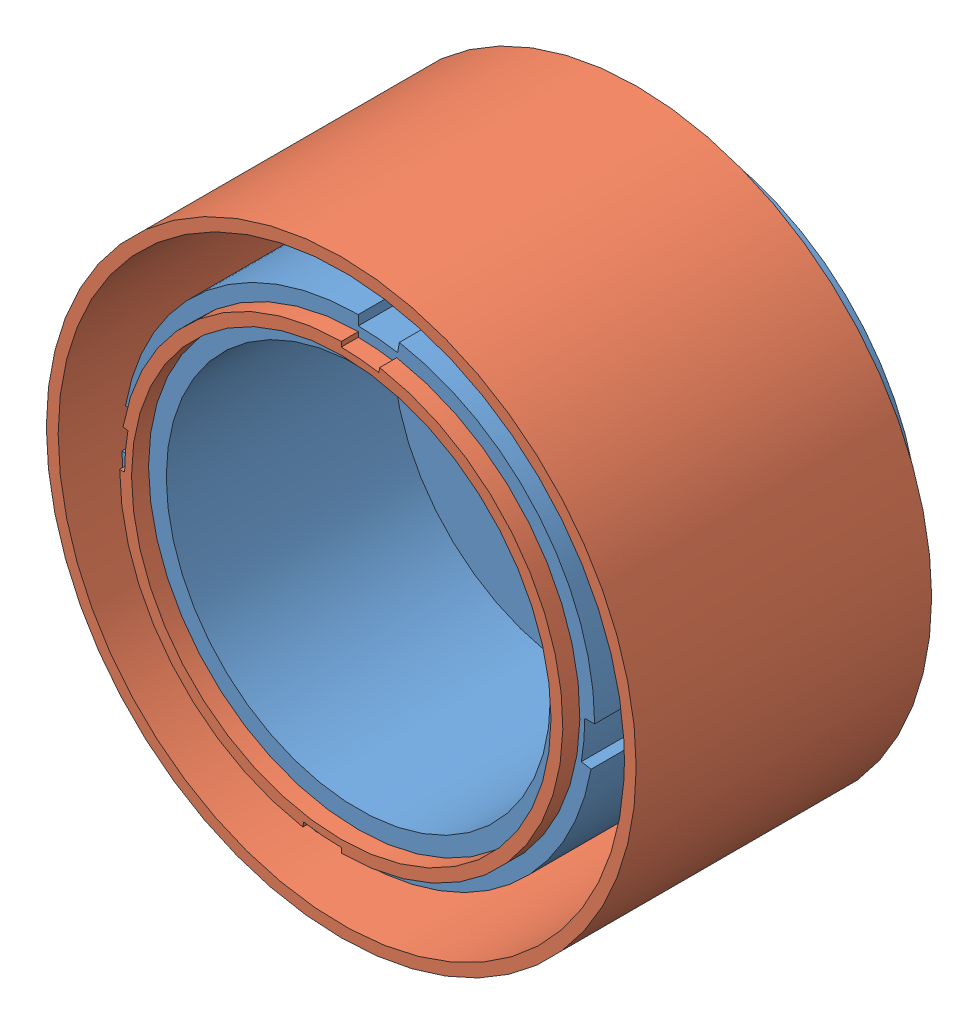
SolidWorks assembly Ensamblaje1, configuration Predeterminado. Lengths in mm.
Overall size (59.9 59.9 34.73).
2 component instances, 2 part files, 1 mates.
Components (placement in the parent):
- Llanta-1: Llanta [Predeterminado] at (1.6095 -0.2012 48) size (48 48 33)
- molde sumo-1: molde sumo [Predeterminado] at (1.6095 -0.2012 36.226) size (59.9 59.9 30)
Mates (geometry in assembly coordinates):
- Concéntrica1: concentric aligned: cylinder of Llanta-1 through (1.6095 -0.2012 64.5) axis (0 0 -1) radius 24; cylinder of molde sumo-1 through (1.6095 -0.2012 66.226) axis (0 0 -1) radius 21.3
